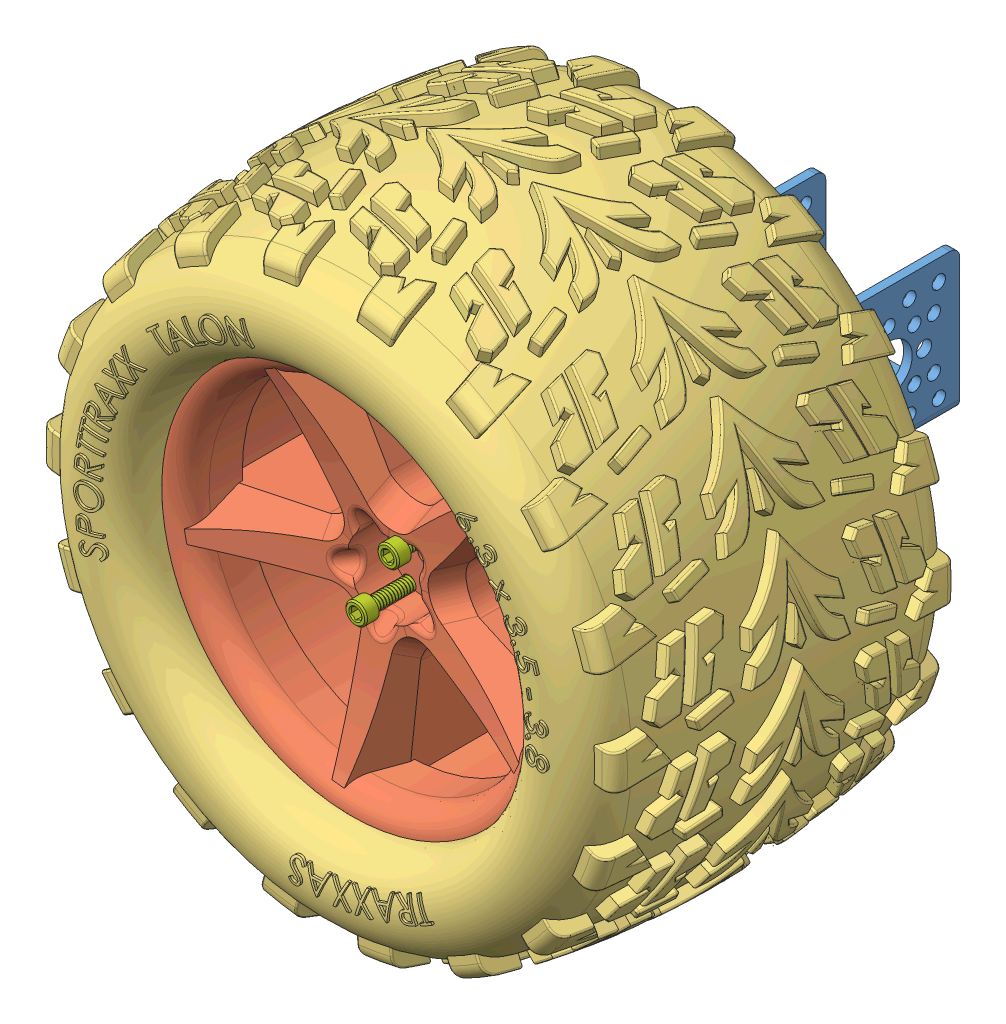
SolidWorks assembly Wheel Assembly, configuration Middle Wheel. Lengths in mm.
Overall size (182.86 183.23 157.75).
15 component instances, 8 part files, 23 mates.
Components (placement in the parent):
- 3 Aluminum Channel-1: 3 Aluminum Channel [Default] at (-17.2943 26.284 30.6898) size (38.1 38.1 76.2)
- Wheel-1: Wheel [Default] at (-70.1316 -42.318 140.7011) x (0 0 1) z (0.106642 0.994297 0) size (106.88 166.05 166.47)
  - Wheel Rim-1: Wheel Rim [Default] at (-5.7009 62.13 94.8184) size (78.74 101.6 101.6)
  - Wheel Tire-1: Wheel Tire [Default] at (-5.7009 62.1295 94.8183) size (106.88 166.05 166.47)
- 25m Bore Side Tapped Clamping Mount-1: 25m Bore Side Tapped Clamping Mount [Default] at (1.1407 51.5007 106.1447) x (1 0 0) z (0 -1 0) size (33.76 11.43 64.42)
  - 25m Bore Side Tapped Clamping Mount-1: 25m Bore Side Tapped Clamping Mount [Default] at (0.615 -8.6446 6.1668) size (33.76 7.62 39.7)
  - #6-32 0_5 Bolt-1: #6-32 0_5 Bolt [Default] at (-31.135 -4.8346 -13.2719) x (0 0.2706 0.962692) z (-1 0 0) size (5.57 5.57 16.21)
- 25mm Motor and Encoder-1: 25mm Motor and Encoder [Default] at (-28.8188 49.6309 104.1252) x (0.990268 -0.139173 0) z (0 0 1) size (25 32.85 80)
- 6-32_SHCS-1: 6-32_SHCS [6-32 SHCS X .250] at (14.4557 58.8044 101.3102) x (0 0 -1) z (1 0 0) size (5.74 5.74 9.86)
- 6-32_SHCS-2: 6-32_SHCS [6-32 SHCS X .250] at (-10.9443 58.8044 101.3102) x (0 0.924225 0.381849) z (-1 0 0) size (5.74 5.74 9.86)
- 6-32_SHCS-3: 6-32_SHCS [6-32 SHCS X .250] at (-10.9443 31.8636 101.3102) x (0 0.924225 0.381849) z (-1 0 0) size (5.74 5.74 9.86)
- 6-32_SHCS-4: 6-32_SHCS [6-32 SHCS X .250] at (14.4557 31.8636 101.3102) x (0 0 -1) z (1 0 0) size (5.74 5.74 9.86)
- 6-32_SHCS-5: 6-32_SHCS [6-32 SHCS X 1.250] at (6.0479 54.1206 133.797) x (-0.106642 -0.994297 0) z (0 0 1) size (5.74 5.74 35.26)
- 6-32_SHCS-6: 6-32_SHCS [6-32 SHCS X 1.250] at (-2.5366 36.5473 133.797) x (-0.106642 -0.994297 0) z (0 0 1) size (5.74 5.74 35.26)
- 4mm Face Tapped Clamping Hub-1: 4mm Face Tapped Clamping Hub [Default] at (1.7557 45.334 125.4752) x (0.945719 0.324986 0) z (0.324986 -0.945719 0) size (20.57 9.64 26.29)
Mates (geometry in assembly coordinates):
- Concentric1: concentric aligned: cylinder of Wheel-1/Wheel Rim-1 through (-2.5366 36.5473 174.3702) axis (0 0 -1) radius 1.905; cylinder of 6-32_SHCS-6 through (-2.5366 36.5473 178.247) axis (0 0 -1) radius 2.8702
- Concentric2: concentric aligned: cylinder of Wheel-1/Wheel Rim-1 through (6.0479 54.1206 174.3702) axis (0 0 -1) radius 1.905; cylinder of 6-32_SHCS-5 through (6.0479 54.1206 178.247) axis (0 0 -1) radius 2.8702
- Concentric3: concentric anti-aligned: cylinder of 25m Bore Side Tapped Clamping Mount-1/25m Bore Side Tapped Clamping Mount-1 through (1.7557 45.334 105.1202) axis (0 0 -1) radius 12.5; cylinder of 25mm Motor and Encoder-1 through (1.7557 45.334 97.5002) axis (0 0 1) radius 12.5
- Concentric4: concentric anti-aligned: cylinder of 25mm Motor and Encoder-1 through (1.7557 45.334 122.5002) axis (0 0 1) radius 2; cylinder of 4mm Face Tapped Clamping Hub-1 through (1.7557 45.334 125.4752) axis (0 0 -1) radius 2
- Coincident1: coincident aligned: plane of 25mm Motor and Encoder-1 through (1.7557 45.334 135.0002) normal (0 0 1); plane of 4mm Face Tapped Clamping Hub-1 through (1.7557 45.334 135.0002) normal (0 0 1)
- Coincident2: coincident aligned: plane of 25m Bore Side Tapped Clamping Mount-1/25m Bore Side Tapped Clamping Mount-1 through (15.2253 31.8644 97.5002) normal (0 0 -1); plane of 25mm Motor and Encoder-1 through (1.7557 45.334 97.5002) normal (0 0 -1)
- Concentric5: concentric anti-aligned: cylinder of 3 Aluminum Channel-1 through (20.8057 58.8044 101.3102) axis (1 0 0) radius 1.778; cylinder of 25m Bore Side Tapped Clamping Mount-1/25m Bore Side Tapped Clamping Mount-1 through (-15.0083 58.8044 101.3102) axis (-1 0 0) radius 1.3526
- Concentric6: concentric anti-aligned: cylinder of 3 Aluminum Channel-1 through (20.8057 31.8636 101.3102) axis (1 0 0) radius 1.778; cylinder of 25m Bore Side Tapped Clamping Mount-1/25m Bore Side Tapped Clamping Mount-1 through (-15.0083 31.8636 101.3102) axis (-1 0 0) radius 1.3526
- Coincident3: coincident anti-aligned: plane of 3 Aluminum Channel-1 through (18.5197 28.57 106.8898) normal (-1 0 0); plane of 25m Bore Side Tapped Clamping Mount-1/25m Bore Side Tapped Clamping Mount-1 through (18.5197 61.9786 105.1202) normal (1 0 0)
- Concentric7: concentric anti-aligned: cylinder of 3 Aluminum Channel-1 through (20.8057 58.8044 101.3102) axis (1 0 0) radius 1.778; cylinder of 6-32_SHCS-1 through (33.5057 58.8044 101.3102) axis (-1 0 0) radius 2.8702
- Concentric8: concentric aligned: cylinder of 3 Aluminum Channel-1 through (20.8057 58.8044 101.3102) axis (1 0 0) radius 1.778; cylinder of 6-32_SHCS-2 through (-29.9943 58.8044 101.3102) axis (1 0 0) radius 2.8702
- Concentric9: concentric anti-aligned: cylinder of 3 Aluminum Channel-1 through (20.8057 31.8636 101.3102) axis (1 0 0) radius 1.778; cylinder of 6-32_SHCS-4 through (33.5057 31.8636 101.3102) axis (-1 0 0) radius 2.8702
- Concentric10: concentric aligned: cylinder of 3 Aluminum Channel-1 through (20.8057 31.8636 101.3102) axis (1 0 0) radius 1.778; cylinder of 6-32_SHCS-3 through (-29.9943 31.8636 101.3102) axis (1 0 0) radius 2.8702
- Coincident4: coincident anti-aligned: plane of 3 Aluminum Channel-1 through (-17.2943 26.284 106.8898) normal (-1 0 0); plane of 6-32_SHCS-2 through (-17.2943 58.8044 101.3102) normal (1 0 0)
- Coincident5: coincident anti-aligned: plane of 3 Aluminum Channel-1 through (-17.2943 26.284 106.8898) normal (-1 0 0); plane of 6-32_SHCS-3 through (-17.2943 31.8636 101.3102) normal (1 0 0)
- Coincident6: coincident anti-aligned: plane of 3 Aluminum Channel-1 through (20.8057 64.384 106.8898) normal (1 0 0); plane of 6-32_SHCS-4 through (20.8057 31.8636 101.3102) normal (-1 0 0)
- Coincident7: coincident anti-aligned: plane of 3 Aluminum Channel-1 through (20.8057 64.384 106.8898) normal (1 0 0); plane of 6-32_SHCS-1 through (20.8057 58.8044 101.3102) normal (-1 0 0)
- Coincident8: coincident anti-aligned: moEndPointRef_w of Wheel-1/Wheel Rim-1; plane of 6-32_SHCS-6 through (-2.5366 36.5473 165.547) normal (0 0 -1)
- Coincident9: coincident anti-aligned: moEndPointRef_w of Wheel-1/Wheel Rim-1; plane of 6-32_SHCS-5 through (6.0479 54.1206 165.547) normal (0 0 -1)
- Concentric11: concentric anti-aligned: cylinder of 4mm Face Tapped Clamping Hub-1 through (6.0479 54.1206 135.0002) axis (0 0 1) radius 1.3526; cylinder of 6-32_SHCS-5 through (6.0479 54.1206 178.247) axis (0 0 -1) radius 2.8702
- Concentric12: concentric anti-aligned: cylinder of 4mm Face Tapped Clamping Hub-1 through (-2.5366 36.5473 135.0002) axis (0 0 1) radius 1.3526; cylinder of 6-32_SHCS-6 through (-2.5366 36.5473 178.247) axis (0 0 -1) radius 2.8702
- Tangent1: tangent: face of Wheel-1/Wheel Rim-1; plane of 4mm Face Tapped Clamping Hub-1 through (1.7557 45.334 135.0002) normal (0 0 1)
- Parallel1: parallel aligned: plane of 3 Aluminum Channel-1 through (-17.2943 26.284 106.8898) normal (-1 0 0); plane of 25mm Motor and Encoder-1 through (-4.5443 49.2741 60.7002) normal (-1 0 0)
